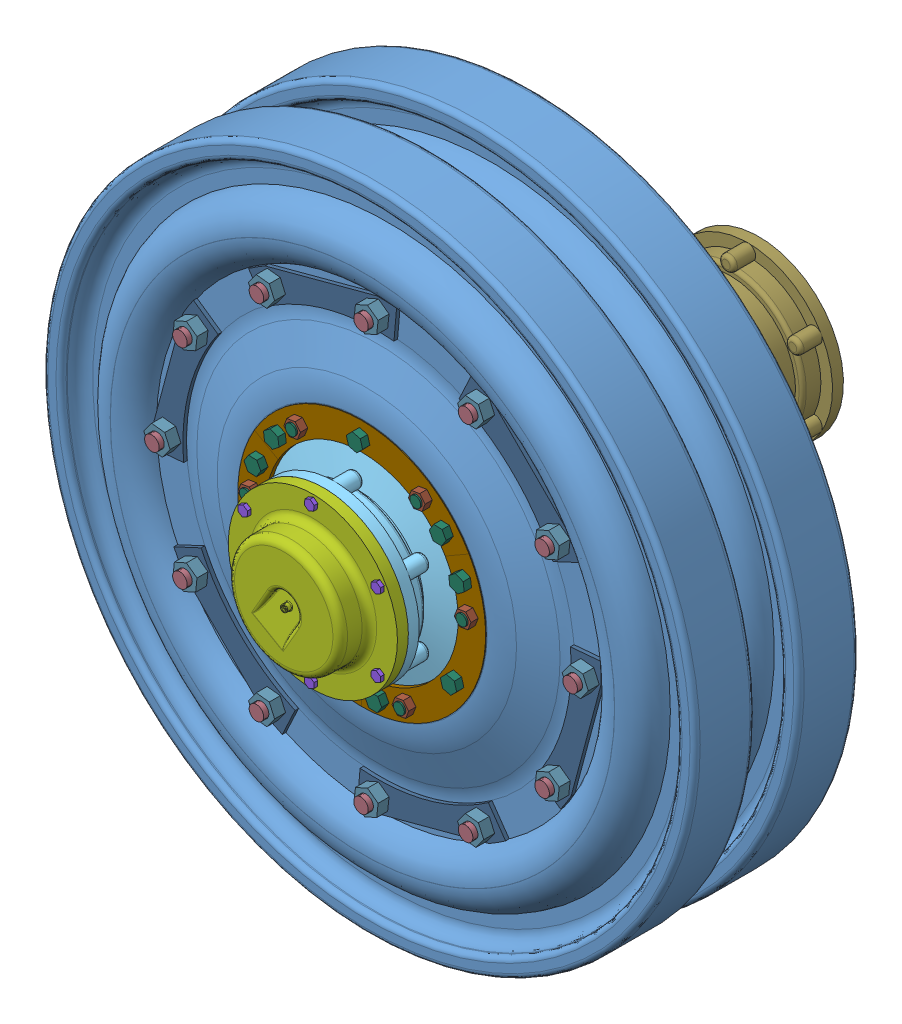
SolidWorks assembly Road Wheel - Outboard, configuration Default. Lengths in mm.
Overall size (31.05 31.05 16.2).
119 component instances, 15 part files, 92 mates.
Components (placement in the parent):
- Road Wheel-1: Road Wheel [Default] at (-21.9237 -2.6593 13.6423) size (22.73 22.73 3.09)
- Road Wheel-2: Road Wheel [Default] at (-21.9237 -2.6593 10.0228) x (0.5 -0.866025 0) z (0 0 -1) size (22.73 22.73 3.09)
- Road Wheel Space-1: Road Wheel Space [Default] at (-21.9237 -2.6593 10.6641) size (15.62 15.62 2.34)
- Road Wheel Bearing Assembly-1: Road Wheel Bearing Assembly [Default] at (-21.6388 -3.4173 13.177) x (0.656083 -0.754689 0) z (-0.754689 -0.656083 0) size (6.56 1.78 6.5)
  - Road Wheel Bearing-1: Road Wheel Bearing [Default] at (-0.759 1.0051 -0.2823) size (6.25 1.78 6.25)
  - Road Wheel Bearing Roller-1: Road Wheel Bearing Roller [Default] at (-0.759 -0.5628 2.4983) x (-0.999426 -0.00354 0.033681) z (0 0.994522 0.104528) size (0.64 0.64 1.4)
  - Road Wheel Bearing Roller-2: Road Wheel Bearing Roller [Default] at (-3.2936 0.8266 -1.7456) x (0.789274 0.103648 0.60523) z (0.090524 -0.994522 0.052264) size (0.64 0.64 1.4)
  - Road Wheel Bearing Roller-3: Road Wheel Bearing Roller [Default] at (-0.759 0.8266 -3.209) x (1 0 0) z (0 -0.994522 0.104528) size (0.64 0.64 1.4)
  - Road Wheel Bearing Roller-4: Road Wheel Bearing Roller [Default] at (0.242 0.8266 -3.0325) x (0.927484 0.003582 0.373846) z (-0.035751 -0.994522 0.098225) size (0.64 0.64 1.4)
  - Road Wheel Bearing Roller-5: Road Wheel Bearing Roller [Default] at (-2.5464 -0.5628 1.8478) x (0.99582 0.061868 0.06719) z (-0.06719 0.994522 0.080073) size (0.64 0.64 1.4)
  - Road Wheel Bearing Roller-6: Road Wheel Bearing Roller [Default] at (-3.4974 -0.5628 0.2005) x (0.979533 0.098182 0.175711) z (-0.10294 0.994522 0.018151) size (0.64 0.64 1.4)
  - Road Wheel Bearing Roller-7: Road Wheel Bearing Roller [Default] at (-2.6402 0.8266 -2.5243) x (0.99582 0.061868 -0.06719) z (0.06719 -0.994522 0.080073) size (0.64 0.64 1.4)
  - Road Wheel Bearing Roller-8: Road Wheel Bearing Roller [Default] at (-3.1671 -0.5628 1.108) x (0.992212 0.085557 0.090524) z (-0.090524 0.994522 0.052264) size (0.64 0.64 1.4)
  - Road Wheel Bearing Roller-9: Road Wheel Bearing Roller [Default] at (-1.71 -0.5628 2.3306) x (0.998836 0.032375 0.035751) z (-0.035751 0.994522 0.098225) size (0.64 0.64 1.4)
  - Road Wheel Bearing Roller-10: Road Wheel Bearing Roller [Default] at (-1.76 0.8266 -3.0325) x (0.998836 0.032375 -0.035751) z (0.035751 -0.994522 0.098225) size (0.64 0.64 1.4)
  - Road Wheel Bearing Roller-11: Road Wheel Bearing Roller [Default] at (-3.6412 0.8266 -0.7905) x (0.986505 0.104412 0.126122) z (0.10294 -0.994522 0.018151) size (0.64 0.64 1.4)
  - Road Wheel Bearing Roller-12: Road Wheel Bearing Roller [Default] at (2.1232 0.8266 -0.7905) x (0.885883 -0.083366 0.456356) z (-0.10294 -0.994522 0.018151) size (0.64 0.64 1.4)
  - Road Wheel Bearing Roller-13: Road Wheel Bearing Roller [Default] at (1.6491 -0.5628 1.108) x (0.992212 -0.085557 -0.090524) z (0.090524 0.994522 0.052264) size (0.64 0.64 1.4)
  - Road Wheel Bearing Roller-14: Road Wheel Bearing Roller [Default] at (1.0284 -0.5628 1.8478) x (0.874291 -0.097355 0.47554) z (0.06719 0.994522 0.080073) size (0.64 0.64 1.4)
  - Road Wheel Bearing Roller-15: Road Wheel Bearing Roller [Default] at (1.1222 0.8266 -2.5243) x (0.913673 -0.093574 -0.395532) z (-0.06719 -0.994522 0.080073) size (0.64 0.64 1.4)
  - Road Wheel Bearing Roller-16: Road Wheel Bearing Roller [Default] at (1.7756 0.8266 -1.7456) x (0.899555 -0.059136 0.432785) z (-0.090524 -0.994522 0.052264) size (0.64 0.64 1.4)
  - Road Wheel Bearing Roller-17: Road Wheel Bearing Roller [Default] at (1.9794 -0.5628 0.2005) x (0.989592 -0.100551 -0.10294) z (0.10294 0.994522 0.018151) size (0.64 0.64 1.4)
  - Road Wheel Bearing Roller-18: Road Wheel Bearing Roller [Default] at (0.192 -0.5628 2.3306) x (0.70634 -0.094677 0.701512) z (0.035751 0.994522 0.098225) size (0.64 0.64 1.4)
- Road Wheel Bearing Assembly-2: Road Wheel Bearing Assembly [Default] at (-21.3767 -3.2564 10.4881) x (0.37605 -0.926599 0) z (0.926599 0.37605 0) size (6.56 1.78 6.5)
  - Road Wheel Bearing-1: Road Wheel Bearing [Default] at (-0.759 1.0051 -0.2823) size (6.25 1.78 6.25)
  - Road Wheel Bearing Roller-1: Road Wheel Bearing Roller [Default] at (-0.759 -0.5628 2.4983) x (-0.999426 -0.00354 0.033681) z (0 0.994522 0.104528) size (0.64 0.64 1.4)
  - Road Wheel Bearing Roller-2: Road Wheel Bearing Roller [Default] at (-3.2936 0.8266 -1.7456) x (0.789274 0.103648 0.60523) z (0.090524 -0.994522 0.052264) size (0.64 0.64 1.4)
  - Road Wheel Bearing Roller-3: Road Wheel Bearing Roller [Default] at (-0.759 0.8266 -3.209) x (1 0 0) z (0 -0.994522 0.104528) size (0.64 0.64 1.4)
  - Road Wheel Bearing Roller-4: Road Wheel Bearing Roller [Default] at (0.242 0.8266 -3.0325) x (0.927484 0.003582 0.373846) z (-0.035751 -0.994522 0.098225) size (0.64 0.64 1.4)
  - Road Wheel Bearing Roller-5: Road Wheel Bearing Roller [Default] at (-2.5464 -0.5628 1.8478) x (0.99582 0.061868 0.06719) z (-0.06719 0.994522 0.080073) size (0.64 0.64 1.4)
  - Road Wheel Bearing Roller-6: Road Wheel Bearing Roller [Default] at (-3.4974 -0.5628 0.2005) x (0.979533 0.098182 0.175711) z (-0.10294 0.994522 0.018151) size (0.64 0.64 1.4)
  - Road Wheel Bearing Roller-7: Road Wheel Bearing Roller [Default] at (-2.6402 0.8266 -2.5243) x (0.99582 0.061868 -0.06719) z (0.06719 -0.994522 0.080073) size (0.64 0.64 1.4)
  - Road Wheel Bearing Roller-8: Road Wheel Bearing Roller [Default] at (-3.1671 -0.5628 1.108) x (0.992212 0.085557 0.090524) z (-0.090524 0.994522 0.052264) size (0.64 0.64 1.4)
  - Road Wheel Bearing Roller-9: Road Wheel Bearing Roller [Default] at (-1.71 -0.5628 2.3306) x (0.998836 0.032375 0.035751) z (-0.035751 0.994522 0.098225) size (0.64 0.64 1.4)
  - Road Wheel Bearing Roller-10: Road Wheel Bearing Roller [Default] at (-1.76 0.8266 -3.0325) x (0.998836 0.032375 -0.035751) z (0.035751 -0.994522 0.098225) size (0.64 0.64 1.4)
  - Road Wheel Bearing Roller-11: Road Wheel Bearing Roller [Default] at (-3.6412 0.8266 -0.7905) x (0.986505 0.104412 0.126122) z (0.10294 -0.994522 0.018151) size (0.64 0.64 1.4)
  - Road Wheel Bearing Roller-12: Road Wheel Bearing Roller [Default] at (2.1232 0.8266 -0.7905) x (0.885883 -0.083366 0.456356) z (-0.10294 -0.994522 0.018151) size (0.64 0.64 1.4)
  - Road Wheel Bearing Roller-13: Road Wheel Bearing Roller [Default] at (1.6491 -0.5628 1.108) x (0.992212 -0.085557 -0.090524) z (0.090524 0.994522 0.052264) size (0.64 0.64 1.4)
  - Road Wheel Bearing Roller-14: Road Wheel Bearing Roller [Default] at (1.0284 -0.5628 1.8478) x (0.874291 -0.097355 0.47554) z (0.06719 0.994522 0.080073) size (0.64 0.64 1.4)
  - Road Wheel Bearing Roller-15: Road Wheel Bearing Roller [Default] at (1.1222 0.8266 -2.5243) x (0.913673 -0.093574 -0.395532) z (-0.06719 -0.994522 0.080073) size (0.64 0.64 1.4)
  - Road Wheel Bearing Roller-16: Road Wheel Bearing Roller [Default] at (1.7756 0.8266 -1.7456) x (0.899555 -0.059136 0.432785) z (-0.090524 -0.994522 0.052264) size (0.64 0.64 1.4)
  - Road Wheel Bearing Roller-17: Road Wheel Bearing Roller [Default] at (1.9794 -0.5628 0.2005) x (0.989592 -0.100551 -0.10294) z (0.10294 0.994522 0.018151) size (0.64 0.64 1.4)
  - Road Wheel Bearing Roller-18: Road Wheel Bearing Roller [Default] at (0.192 -0.5628 2.3306) x (0.70634 -0.094677 0.701512) z (0.035751 0.994522 0.098225) size (0.64 0.64 1.4)
- Road Wheel Bearing Cover-1: Road Wheel Bearing Cover [Default] at (-21.9237 -2.6593 14.563) x (-0.04964 -0.998767 0) z (-0.998767 0.04964 0) size (8.64 2.08 8.64)
- Road Wheel Axle Main Nut-3: Road Wheel Axle Main Nut [Default] at (-21.4032 -5.4723 14.7408) size (3.1 3.08 1.27)
- Road Wheel Grease Cover-1: Road Wheel Grease Cover [Default] at (-21.9237 -2.6593 16.2648) x (0.5 0.866025 0) z (0.866025 -0.5 0) size (5.89 1.41 5.89)
- Road Wheel Grease Cover Bolt-1: Road Wheel Grease Cover Bolt [Default] at (-21.9237 -5.3382 16.6458) x (-0.999673 -0.025557 0) z (0 0 -1) size (0.34 0.38 1.4)
- Road Wheel Grease Cover Bolt-2: Road Wheel Grease Cover Bolt [Default] at (-21.9237 0.0196 16.6458) x (0.54039 0.841415 0) z (0 0 -1) size (0.34 0.38 1.4)
- Road Wheel Grease Cover Bolt-3: Road Wheel Grease Cover Bolt [Default] at (-19.6038 -3.9987 16.6458) x (-0.999673 -0.025557 0) z (0 0 -1) size (0.34 0.38 1.4)
- Road Wheel Grease Cover Bolt-4: Road Wheel Grease Cover Bolt [Default] at (-24.2437 -1.3199 16.6458) x (-0.999673 -0.025557 0) z (0 0 -1) size (0.34 0.38 1.4)
- Road Wheel Grease Cover Bolt-5: Road Wheel Grease Cover Bolt [Default] at (-24.2437 -3.9987 16.6458) x (-0.999673 -0.025557 0) z (0 0 -1) size (0.34 0.38 1.4)
- Road Wheel Grease Cover Bolt-6: Road Wheel Grease Cover Bolt [Default] at (-19.6038 -1.3199 16.6458) x (-0.999673 -0.025557 0) z (0 0 -1) size (0.34 0.38 1.4)
- Retainer Plate-1: Retainer Plate [Default] at (-21.9237 -2.6593 14.563) x (-0.5 0.866025 0) z (0 0 1) size (7.48 2.64 0.38)
- Retainer Plate-2: Retainer Plate [Default] at (-21.9237 -2.6593 14.563) x (-0.5 -0.866025 0) z (0 0 1) size (7.48 2.64 0.38)
- Retainer Plate-3: Retainer Plate [Default] at (-21.9237 -2.6593 14.563) size (7.48 2.64 0.38)
- Retainer Plate-4: Retainer Plate [Default] at (-21.9237 -2.6593 8.721) x (-0.5 -0.866025 0) z (0 0 1) size (7.48 2.64 0.38)
- Retainer Plate-5: Retainer Plate [Default] at (-21.9237 -2.6593 8.721) size (7.48 2.64 0.38)
- Retainer Plate-6: Retainer Plate [Default] at (-21.9237 -2.6593 8.721) x (-0.5 0.866025 0) z (0 0 1) size (7.48 2.64 0.38)
- Nut Retainer Plate-1: Nut Retainer Plate [Default] at (-21.9237 -2.6593 14.2836) x (0.5 0.866025 0) z (0 0 1) size (5.16 2.27 0.13)
- Nut Retainer Plate-2: Nut Retainer Plate [Default] at (-21.9237 -2.6593 14.2836) size (5.16 2.27 0.13)
- Nut Retainer Plate-3: Nut Retainer Plate [Default] at (-21.9237 -2.6593 14.2836) x (0.5 -0.866025 0) z (0 0 1) size (5.16 2.27 0.13)
- Nut Retainer Plate-4: Nut Retainer Plate [Default] at (-21.9237 -2.6593 14.2836) x (-0.5 0.866025 0) z (0 0 1) size (5.16 2.27 0.13)
- Nut Retainer Plate-5: Nut Retainer Plate [Default] at (-21.9237 -2.6593 14.2836) x (-1 0 0) z (0 0 1) size (5.16 2.27 0.13)
- Nut Retainer Plate-6: Nut Retainer Plate [Default] at (-21.9237 -2.6593 14.2836) x (-0.5 -0.866025 0) z (0 0 1) size (5.16 2.27 0.13)
- Road Wheel Bearing nut-2: Road Wheel Bearing nut [Default] at (-25.4383 -3.1945 8.467) size (0.58 0.55 0.25)
- Wheel Bearing Cover - Long-1: Wheel Bearing Cover - Long [Default] at (-21.9237 -2.6593 9.102) x (0.04964 -0.998767 0) z (0.998767 0.04964 0) size (8.64 8 8.64)
- Road Wheel Main Bolt-1: Road Wheel Main Bolt [Default] at (-28.2349 -6.303 9.3814) x (0.131887 0.991265 0) z (0 0 1) size (0.95 1.02 5.97)
- Road Wheel Main Nut-4: Road Wheel Main Nut [Default] at (-29.206 -3.6122 14.4106) x (-0.986683 -0.162654 0) z (0 0 1) size (0.89 0.88 0.38)
- Road Wheel Bearing Bolt-1: Road Wheel Bearing Bolt [Default] at (-25.2013 -4.5516 14.944) x (-0.923728 -0.383049 0) z (0 0 -1) size (0.54 0.58 6.78)
- Road Wheel Main Nut-5: Road Wheel Main Nut [Default] at (-28.7068 0.1566 14.4106) x (-0.93582 0.352479 0) z (0 0 1) size (0.89 0.88 0.38)
- Road Wheel Main Nut-6: Road Wheel Main Nut [Default] at (-26.3901 3.1709 14.4106) x (-0.634204 0.773166 0) z (0 0 1) size (0.89 0.88 0.38)
- Road Wheel Main Nut-7: Road Wheel Main Nut [Default] at (-22.8766 4.6229 14.4106) x (-0.162654 0.986683 0) z (0 0 1) size (0.89 0.88 0.38)
- Road Wheel Main Nut-8: Road Wheel Main Nut [Default] at (-19.1078 4.1237 14.4106) x (0.352479 0.93582 0) z (0 0 1) size (0.89 0.88 0.38)
- Road Wheel Main Nut-9: Road Wheel Main Nut [Default] at (-16.0936 1.807 14.4106) x (0.773166 0.634204 0) z (0 0 1) size (0.89 0.88 0.38)
- Road Wheel Main Nut-10: Road Wheel Main Nut [Default] at (-14.6415 -1.7064 14.4106) x (0.986683 0.162654 0) z (0 0 1) size (0.89 0.88 0.38)
- Road Wheel Main Nut-11: Road Wheel Main Nut [Default] at (-15.1407 -5.4752 14.4106) x (0.93582 -0.352479 0) z (0 0 1) size (0.89 0.88 0.38)
- Road Wheel Main Nut-12: Road Wheel Main Nut [Default] at (-17.4574 -8.4895 14.4106) x (0.634204 -0.773166 0) z (0 0 1) size (0.89 0.88 0.38)
- Road Wheel Main Nut-13: Road Wheel Main Nut [Default] at (-20.9709 -9.9416 14.4106) x (0.162654 -0.986683 0) z (0 0 1) size (0.89 0.88 0.38)
- Road Wheel Main Nut-14: Road Wheel Main Nut [Default] at (-24.7397 -9.4424 14.4106) x (-0.352479 -0.93582 0) z (0 0 1) size (0.89 0.88 0.38)
- Road Wheel Main Nut-15: Road Wheel Main Nut [Default] at (-27.7539 -7.1256 14.4106) x (-0.773166 -0.634204 0) z (0 0 1) size (0.89 0.88 0.38)
- Road Wheel Main Bolt-2: Road Wheel Main Bolt [Default] at (-29.2112 -2.6593 9.3814) x (0.60985 0.792517 0) z (0 0 1) size (0.95 1.02 5.97)
- Road Wheel Main Bolt-3: Road Wheel Main Bolt [Default] at (-28.2349 0.9844 9.3814) x (0.924404 0.381415 0) z (0 0 1) size (0.95 1.02 5.97)
- Road Wheel Main Bolt-4: Road Wheel Main Bolt [Default] at (-25.5675 3.6518 9.3814) x (0.991265 -0.131887 0) z (0 0 1) size (0.95 1.02 5.97)
- Road Wheel Main Bolt-5: Road Wheel Main Bolt [Default] at (-21.9237 4.6282 9.3814) x (0.792517 -0.60985 0) z (0 0 1) size (0.95 1.02 5.97)
- Road Wheel Main Bolt-6: Road Wheel Main Bolt [Default] at (-18.28 3.6518 9.3814) x (0.381415 -0.924404 0) z (0 0 1) size (0.95 1.02 5.97)
- Road Wheel Main Bolt-7: Road Wheel Main Bolt [Default] at (-15.6126 0.9844 9.3814) x (-0.131887 -0.991265 0) z (0 0 1) size (0.95 1.02 5.97)
- Road Wheel Main Bolt-8: Road Wheel Main Bolt [Default] at (-14.6363 -2.6593 9.3814) x (-0.60985 -0.792517 0) z (0 0 1) size (0.95 1.02 5.97)
- Road Wheel Main Bolt-9: Road Wheel Main Bolt [Default] at (-15.6126 -6.303 9.3814) x (-0.924404 -0.381415 0) z (0 0 1) size (0.95 1.02 5.97)
- Road Wheel Main Bolt-10: Road Wheel Main Bolt [Default] at (-18.28 -8.9704 9.3814) x (-0.991265 0.131887 0) z (0 0 1) size (0.95 1.02 5.97)
- Road Wheel Main Bolt-11: Road Wheel Main Bolt [Default] at (-21.9237 -9.9468 9.3814) x (-0.792517 0.60985 0) z (0 0 1) size (0.95 1.02 5.97)
- Road Wheel Main Bolt-12: Road Wheel Main Bolt [Default] at (-25.5675 -8.9704 9.3814) x (-0.381415 0.924404 0) z (0 0 1) size (0.95 1.02 5.97)
- Road Wheel Bearing Bolt-2: Road Wheel Bearing Bolt [Default] at (-22.5809 -6.3864 14.944) x (0.698183 -0.71592 0) z (0 0 -1) size (0.54 0.58 6.78)
- Road Wheel Bearing Bolt-3: Road Wheel Bearing Bolt [Default] at (-23.5232 -6.0893 8.721) size (0.54 0.58 6.78)
- Road Wheel Bearing Bolt-4: Road Wheel Bearing Bolt [Default] at (-25.6939 -2.3295 8.721) size (0.54 0.58 6.78)
- Road Wheel Bearing Bolt-5: Road Wheel Bearing Bolt [Default] at (-25.4801 -1.3649 14.944) x (0.078468 -0.996917 0) z (0 0 -1) size (0.54 0.58 6.78)
- Road Wheel Bearing nut-3: Road Wheel Bearing nut [Default] at (-25.9309 -0.9724 14.944) size (0.58 0.55 0.25)
- Road Wheel Bearing nut-4: Road Wheel Bearing nut [Default] at (-23.7602 -4.7322 14.944) size (0.58 0.55 0.25)
- Road Wheel Bearing nut-5: Road Wheel Bearing nut [Default] at (-22.8179 -5.0293 8.467) size (0.58 0.55 0.25)
- Road Wheel Bearing nut-6: Road Wheel Bearing nut [Default] at (-25.7171 -0.0078 8.467) size (0.58 0.55 0.25)
- Road Wheel Bearing nut-7: Road Wheel Bearing nut [Default] at (-19.4242 -2.2487 8.467) x (-0.5 0.866025 0) z (0 0 1) size (0.58 0.55 0.25)
- Road Wheel Bearing nut-8: Road Wheel Bearing nut [Default] at (-23.5291 -0.6999 8.467) x (-0.5 -0.866025 0) z (0 0 1) size (0.58 0.55 0.25)
- Road Wheel Bearing nut-9: Road Wheel Bearing nut [Default] at (-19.703 -5.4354 8.467) x (-0.5 0.866025 0) z (0 0 1) size (0.58 0.55 0.25)
- Road Wheel Bearing nut-10: Road Wheel Bearing nut [Default] at (-20.6299 0.652 8.467) x (-0.5 -0.866025 0) z (0 0 1) size (0.58 0.55 0.25)
- Road Wheel Bearing nut-11: Road Wheel Bearing nut [Default] at (-22.3233 -7.2702 8.467) x (-0.5 0.866025 0) z (0 0 1) size (0.58 0.55 0.25)
- Road Wheel Bearing nut-12: Road Wheel Bearing nut [Default] at (-17.7308 -0.6999 8.467) x (-0.5 -0.866025 0) z (0 0 1) size (0.58 0.55 0.25)
- Road Wheel Bearing Bolt-6: Road Wheel Bearing Bolt [Default] at (-21.2666 -6.3864 14.944) x (0.824121 0.566414 0) z (0 0 -1) size (0.54 0.58 6.78)
- Road Wheel Bearing Bolt-7: Road Wheel Bearing Bolt [Default] at (-19.0246 -0.2266 14.944) x (-0.902589 0.430503 0) z (0 0 -1) size (0.54 0.58 6.78)
- Road Wheel Bearing Bolt-8: Road Wheel Bearing Bolt [Default] at (-20.3243 -6.0893 8.721) x (-0.5 0.866025 0) z (0 0 1) size (0.54 0.58 6.78)
- Road Wheel Bearing Bolt-9: Road Wheel Bearing Bolt [Default] at (-19.753 0.4409 8.721) x (-0.5 -0.866025 0) z (0 0 1) size (0.54 0.58 6.78)
- Road Wheel Bearing nut-13: Road Wheel Bearing nut [Default] at (-21.3811 -6.9731 14.944) x (-0.5 0.866025 0) z (0 0 1) size (0.58 0.55 0.25)
- Road Wheel Bearing nut-14: Road Wheel Bearing nut [Default] at (-18.4592 -0.0325 14.944) x (-0.5 -0.866025 0) z (0 0 1) size (0.58 0.55 0.25)
- Road Wheel Bearing Bolt-10: Road Wheel Bearing Bolt [Default] at (-18.6462 -4.5516 14.944) x (0.793594 -0.608447 0) z (0 0 -1) size (0.54 0.58 6.78)
- Road Wheel Bearing Bolt-11: Road Wheel Bearing Bolt [Default] at (-21.9237 1.1253 14.944) x (0.130134 0.991496 0) z (0 0 -1) size (0.54 0.58 6.78)
- Road Wheel Bearing nut-15: Road Wheel Bearing nut [Default] at (-19.2103 -3.2133 14.944) x (-0.5 0.866025 0) z (0 0 1) size (0.58 0.55 0.25)
- Road Wheel Bearing nut-16: Road Wheel Bearing nut [Default] at (-22.8007 -0.0325 14.944) x (-0.5 -0.866025 0) z (0 0 1) size (0.58 0.55 0.25)
- Road Wheel Bearing Bolt-12: Road Wheel Bearing Bolt [Default] at (-18.1535 -2.3295 8.721) x (-0.5 0.866025 0) z (0 0 1) size (0.54 0.58 6.78)
- Road Wheel Bearing Bolt-13: Road Wheel Bearing Bolt [Default] at (-24.0945 0.4409 8.721) x (-0.5 -0.866025 0) z (0 0 1) size (0.54 0.58 6.78)
- Road Wheel Bearing Bolt-14: Road Wheel Bearing Bolt [Default] at (-18.3674 -1.3649 14.944) x (0.270913 0.962604 0) z (0 0 -1) size (0.54 0.58 6.78)
- Road Wheel Bearing Bolt-15: Road Wheel Bearing Bolt [Default] at (-24.8229 -0.2266 14.944) x (-0.969096 -0.246684 0) z (0 0 -1) size (0.54 0.58 6.78)
Mates (geometry in assembly coordinates):
- Concentric1: concentric aligned: cylinder of Road Wheel-1 through (-21.9237 -2.6593 14.69) axis (0 0 -1) radius 11.3665; cylinder of Road Wheel Space-1 through (-21.9237 -2.6593 13.0009) axis (0 0 -1) radius 6.7644
- Coincident1: coincident anti-aligned: plane of Road Wheel-1 through (-21.9237 -2.6593 13.0009) normal (0 0 -1); plane of Road Wheel Space-1 through (-21.9237 -2.6593 13.0009) normal (0 0 1)
- Concentric2: concentric aligned: cylinder of Road Wheel-1 through (-25.5675 3.6518 15.002) axis (0 0 -1) radius 0.254; cylinder of Road Wheel Space-1 through (-25.5675 3.6518 13.0009) axis (0 0 -1) radius 0.3175
- Coincident2: coincident anti-aligned: plane of Road Wheel-2 through (-21.9237 -2.6593 10.6641) normal (0 0 1); plane of Road Wheel Space-1 through (-21.9237 -2.6593 10.6641) normal (0 0 -1)
- Concentric3: concentric anti-aligned: cylinder of Road Wheel-1 through (-21.9237 -2.6593 14.69) axis (0 0 -1) radius 11.3665; cylinder of Road Wheel-2 through (-21.9237 -2.6593 8.975) axis (0 0 1) radius 11.3665
- Coincident3: coincident aligned: plane of Road Wheel-1 through (-21.9237 -2.6593 14.182) normal (0 0 1); plane of Road Wheel Bearing Assembly-1/Road Wheel Bearing-1 through (-21.9237 -2.6593 14.182) normal (0 0 1)
- Concentric5: concentric anti-aligned: cylinder of Road Wheel-1 through (-21.9237 -2.6593 14.9186) axis (0 0 -1) radius 4.318; cylinder of Road Wheel Bearing Assembly-1/Road Wheel Bearing-1 through (-21.9237 -2.6593 12.404) axis (0 0 1) radius 1.1303
- Coincident4: coincident aligned: plane of Road Wheel-2 through (-21.9237 -2.6593 9.483) normal (0 0 -1); plane of Road Wheel Bearing Assembly-2/Road Wheel Bearing-1 through (-21.9237 -2.6593 9.483) normal (0 0 -1)
- Concentric6: concentric anti-aligned: cylinder of Road Wheel-2 through (-21.9237 -2.6593 8.7464) axis (0 0 1) radius 4.318; cylinder of Road Wheel Bearing Assembly-2/Road Wheel Bearing-1 through (-21.9237 -2.6593 11.261) axis (0 0 -1) radius 1.1303
- Coincident5: coincident anti-aligned: plane of Road Wheel-1 through (-21.9237 -2.6593 14.182) normal (0 0 1); plane of Road Wheel Bearing Cover-1 through (-21.9237 -2.6593 14.182) normal (0 0 -1)
- Concentric7: concentric anti-aligned: cylinder of Road Wheel-1 through (-21.9237 -2.6593 14.9186) axis (0 0 -1) radius 4.318; cylinder of Road Wheel Bearing Cover-1 through (-21.9237 -2.6593 14.182) axis (0 0 1) radius 4.318
- Concentric8: concentric anti-aligned: cylinder of Road Wheel-1 through (-21.9237 1.1253 11.2937) axis (0 0 1) radius 0.1905; cylinder of Road Wheel Bearing Cover-1 through (-21.9237 1.1253 15.1018) axis (0 0 -1) radius 0.1905
- Coincident6: coincident anti-aligned: plane of Road Wheel Bearing Cover-1 through (-21.9237 -2.6593 14.7408) normal (0 0 1); plane of Road Wheel Axle Main Nut-3 through (-19.9489 -0.7189 14.7408) normal (0 0 -1)
- Concentric9: concentric anti-aligned: cylinder of Road Wheel Bearing Cover-1 through (-21.9237 -2.6593 10.8414) axis (0 0 1) radius 1.1811; cylinder of Road Wheel Axle Main Nut-3 through (-21.9237 -2.6593 16.0108) axis (0 0 -1) radius 1.1303
- Coincident7: coincident anti-aligned: plane of Road Wheel Grease Cover-1 through (-21.9237 -2.6593 16.2648) normal (0 0 -1); plane of Road Wheel Bearing Cover-1 through (-21.9237 -2.6593 16.2648) normal (0 0 1)
- Concentric10: concentric aligned: cylinder of Road Wheel Bearing Cover-1 through (-21.9237 -2.6593 16.2648) axis (0 0 -1) radius 2.9464; cylinder of Road Wheel Grease Cover-1 through (-21.9237 -2.6593 16.6458) axis (0 0 -1) radius 2.9464
- Concentric11: concentric aligned: cylinder of Road Wheel Bearing Cover-1 through (-19.6038 -1.3199 15.3758) axis (0 0 1) radius 0.127; cylinder of Road Wheel Grease Cover-1 through (-19.6038 -1.3199 15.9056) axis (0 0 1) radius 0.127
- Coincident8: coincident aligned: plane of Road Wheel Grease Cover Bolt-1 through (-22.0916 -5.4233 16.7728) normal (0 0 1); plane of Road Wheel Grease Cover Bolt-3 through (-19.7717 -4.0839 16.7728) normal (0 0 1)
- Coincident9: coincident aligned: plane of Road Wheel Grease Cover Bolt-1 through (-22.0916 -5.4233 16.7728) normal (0 0 1); plane of Road Wheel Grease Cover Bolt-2 through (-21.8999 0.2063 16.7728) normal (0 0 1)
- Coincident10: coincident aligned: plane of Road Wheel Grease Cover Bolt-2 through (-21.8999 0.2063 16.7728) normal (0 0 1); plane of Road Wheel Grease Cover Bolt-4 through (-24.4116 -1.405 16.7728) normal (0 0 1)
- Coincident11: coincident aligned: plane of Road Wheel Grease Cover Bolt-4 through (-24.4116 -1.405 16.7728) normal (0 0 1); plane of Road Wheel Grease Cover Bolt-5 through (-24.4116 -4.0839 16.7728) normal (0 0 1)
- Coincident12: coincident aligned: plane of Road Wheel Grease Cover Bolt-5 through (-24.4116 -4.0839 16.7728) normal (0 0 1); plane of Road Wheel Grease Cover Bolt-6 through (-19.7717 -1.405 16.7728) normal (0 0 1)
- Concentric12: concentric aligned: cylinder of Road Wheel Grease Cover-1 through (-19.6038 -3.9987 15.9056) axis (0 0 1) radius 0.127; cylinder of Road Wheel Grease Cover Bolt-3 through (-19.6038 -3.9987 15.3758) axis (0 0 1) radius 0.127
- Concentric13: concentric aligned: cylinder of Road Wheel Bearing Cover-1 through (-21.9237 -5.3382 15.3758) axis (0 0 1) radius 0.127; cylinder of Road Wheel Grease Cover Bolt-1 through (-21.9237 -5.3382 15.3758) axis (0 0 1) radius 0.127
- Concentric14: concentric aligned: cylinder of Road Wheel Bearing Cover-1 through (-24.2437 -3.9987 15.3758) axis (0 0 1) radius 0.127; cylinder of Road Wheel Grease Cover Bolt-5 through (-24.2437 -3.9987 15.3758) axis (0 0 1) radius 0.127
- Concentric15: concentric aligned: cylinder of Road Wheel Bearing Cover-1 through (-24.2437 -1.3199 15.3758) axis (0 0 1) radius 0.127; cylinder of Road Wheel Grease Cover Bolt-4 through (-24.2437 -1.3199 15.3758) axis (0 0 1) radius 0.127
- Concentric16: concentric aligned: cylinder of Road Wheel Bearing Cover-1 through (-21.9237 0.0196 15.3758) axis (0 0 1) radius 0.127; cylinder of Road Wheel Grease Cover Bolt-2 through (-21.9237 0.0196 15.3758) axis (0 0 1) radius 0.127
- Concentric17: concentric aligned: cylinder of Road Wheel Grease Cover-1 through (-19.6038 -1.3199 15.9056) axis (0 0 1) radius 0.127; cylinder of Road Wheel Grease Cover Bolt-6 through (-19.6038 -1.3199 15.3758) axis (0 0 1) radius 0.127
- Coincident13: coincident anti-aligned: plane of Road Wheel Grease Cover-1 through (-21.9237 -2.6593 16.6458) normal (0 0 1); plane of Road Wheel Grease Cover Bolt-3 through (-19.7717 -4.0839 16.6458) normal (0 0 -1)
- Coincident14: coincident aligned: plane of Retainer Plate-1 through (-21.9237 -2.6593 14.944) normal (0 0 1); plane of Retainer Plate-2 through (-21.9237 -2.6593 14.944) normal (0 0 1)
- Coincident15: coincident aligned: plane of Retainer Plate-2 through (-21.9237 -2.6593 14.944) normal (0 0 1); plane of Retainer Plate-3 through (-21.9237 -2.6593 14.944) normal (0 0 1)
- Coincident16: coincident anti-aligned: plane of Retainer Plate-2 through (-21.9237 -6.0215 14.944) normal (-1 0 0); plane of Retainer Plate-1 through (-21.9237 -6.0215 14.944) normal (1 0 0)
- Concentric18: concentric aligned: cylinder of Retainer Plate-1 through (-21.9237 -2.6593 14.944) axis (0 0 -1) radius 4.318; cylinder of Retainer Plate-2 through (-21.9237 -2.6593 14.944) axis (0 0 -1) radius 4.318
- Coincident17: coincident anti-aligned: plane of Retainer Plate-3 through (-24.8355 -0.9782 14.944) normal (-0.5 -0.866025 0); plane of Retainer Plate-1 through (-24.8355 -0.9782 14.944) normal (0.5 0.866025 0)
- Concentric19: concentric aligned: cylinder of Retainer Plate-1 through (-21.9237 -2.6593 14.944) axis (0 0 -1) radius 4.318; cylinder of Retainer Plate-3 through (-21.9237 -2.6593 14.944) axis (0 0 -1) radius 4.318
- Coincident18: coincident anti-aligned: plane of Road Wheel Bearing Cover-1 through (-21.9237 -2.6593 14.563) normal (0 0 1); plane of Retainer Plate-3 through (-21.9237 -2.6593 14.563) normal (0 0 -1)
- Concentric20: concentric aligned: cylinder of Road Wheel Bearing Cover-1 through (-25.4801 -1.3649 15.1018) axis (0 0 -1) radius 0.1905; cylinder of Retainer Plate-1 through (-25.4801 -1.3649 14.944) axis (0 0 -1) radius 0.1905
- Coincident19: coincident aligned: plane of Nut Retainer Plate-1 through (-21.9237 -2.6593 14.4106) normal (0 0 1); plane of Nut Retainer Plate-2 through (-21.9237 -2.6593 14.4106) normal (0 0 1)
- Coincident20: coincident aligned: plane of Nut Retainer Plate-2 through (-21.9237 -2.6593 14.4106) normal (0 0 1); plane of Nut Retainer Plate-3 through (-21.9237 -2.6593 14.4106) normal (0 0 1)
- Coincident21: coincident aligned: plane of Nut Retainer Plate-3 through (-21.9237 -2.6593 14.4106) normal (0 0 1); plane of Nut Retainer Plate-4 through (-21.9237 -2.6593 14.4106) normal (0 0 1)
- Coincident22: coincident aligned: plane of Nut Retainer Plate-4 through (-21.9237 -2.6593 14.4106) normal (0 0 1); plane of Nut Retainer Plate-5 through (-21.9237 -2.6593 14.4106) normal (0 0 1)
- Coincident23: coincident aligned: plane of Nut Retainer Plate-5 through (-21.9237 -2.6593 14.4106) normal (0 0 1); plane of Nut Retainer Plate-6 through (-21.9237 -2.6593 14.4106) normal (0 0 1)
- Concentric21: concentric aligned: cylinder of Road Wheel-1 through (-29.2112 -2.6593 15.002) axis (0 0 -1) radius 0.254; cylinder of Nut Retainer Plate-1 through (-29.2112 -2.6593 14.4106) axis (0 0 -1) radius 0.254
- Coincident24: coincident anti-aligned: plane of Road Wheel-1 through (-21.9237 -2.6593 14.2836) normal (0 0 1); plane of Nut Retainer Plate-1 through (-21.9237 -2.6593 14.2836) normal (0 0 -1)
- Concentric22: concentric aligned: cylinder of Road Wheel-1 through (-28.2349 0.9844 15.002) axis (0 0 -1) radius 0.254; cylinder of Nut Retainer Plate-1 through (-28.2349 0.9844 14.4106) axis (0 0 -1) radius 0.254
- Concentric23: concentric aligned: cylinder of Road Wheel-1 through (-25.5675 3.6518 15.002) axis (0 0 -1) radius 0.254; cylinder of Nut Retainer Plate-2 through (-25.5675 3.6518 14.4106) axis (0 0 -1) radius 0.254
- Concentric24: concentric aligned: cylinder of Road Wheel-1 through (-21.9237 4.6282 15.002) axis (0 0 -1) radius 0.254; cylinder of Nut Retainer Plate-2 through (-21.9237 4.6282 14.4106) axis (0 0 -1) radius 0.254
- Concentric25: concentric aligned: cylinder of Road Wheel-1 through (-18.28 3.6518 15.002) axis (0 0 -1) radius 0.254; cylinder of Nut Retainer Plate-3 through (-18.28 3.6518 14.4106) axis (0 0 -1) radius 0.254
- Concentric26: concentric aligned: cylinder of Road Wheel-1 through (-15.6126 0.9844 15.002) axis (0 0 -1) radius 0.254; cylinder of Nut Retainer Plate-3 through (-15.6126 0.9844 14.4106) axis (0 0 -1) radius 0.254
- Concentric27: concentric aligned: cylinder of Road Wheel-1 through (-28.2349 -6.303 15.002) axis (0 0 -1) radius 0.254; cylinder of Nut Retainer Plate-4 through (-28.2349 -6.303 14.4106) axis (0 0 -1) radius 0.254
- Concentric28: concentric aligned: cylinder of Road Wheel-1 through (-25.5675 -8.9704 15.002) axis (0 0 -1) radius 0.254; cylinder of Nut Retainer Plate-4 through (-25.5675 -8.9704 14.4106) axis (0 0 -1) radius 0.254
- Concentric30: concentric aligned: cylinder of Road Wheel-1 through (-21.9237 -9.9468 15.002) axis (0 0 -1) radius 0.254; cylinder of Nut Retainer Plate-5 through (-21.9237 -9.9468 14.4106) axis (0 0 -1) radius 0.254
- Concentric31: concentric aligned: cylinder of Road Wheel-1 through (-18.28 -8.9704 15.002) axis (0 0 -1) radius 0.254; cylinder of Nut Retainer Plate-5 through (-18.28 -8.9704 14.4106) axis (0 0 -1) radius 0.254
- Concentric32: concentric aligned: cylinder of Road Wheel-1 through (-15.6126 -6.303 15.002) axis (0 0 -1) radius 0.254; cylinder of Nut Retainer Plate-6 through (-15.6126 -6.303 14.4106) axis (0 0 -1) radius 0.254
- Concentric33: concentric aligned: cylinder of Road Wheel-1 through (-14.6363 -2.6593 15.002) axis (0 0 -1) radius 0.254; cylinder of Nut Retainer Plate-6 through (-14.6363 -2.6593 14.4106) axis (0 0 -1) radius 0.254
- Concentric34: concentric anti-aligned: cylinder of Road Wheel-1 through (-25.2013 -4.5516 11.2937) axis (0 0 1) radius 0.1905; cylinder of Road Wheel-2 through (-25.2013 -4.5516 12.3713) axis (0 0 -1) radius 0.1905
- Concentric35: concentric aligned: cylinder of Road Wheel Bearing Cover-1 through (-18.6462 -4.5516 15.1018) axis (0 0 -1) radius 0.1905; cylinder of Retainer Plate-2 through (-18.6462 -4.5516 14.944) axis (0 0 -1) radius 0.1905
- Coincident25: coincident anti-aligned: plane of Road Wheel-2 through (-21.9237 -2.6593 9.483) normal (0 0 -1); plane of Wheel Bearing Cover - Long-1 through (-21.9237 -2.6593 9.483) normal (0 0 1)
- Concentric36: concentric anti-aligned: cylinder of Road Wheel-2 through (-21.9237 -2.6593 8.7464) axis (0 0 1) radius 4.318; cylinder of Wheel Bearing Cover - Long-1 through (-21.9237 -2.6593 9.483) axis (0 0 -1) radius 4.318
- Concentric37: concentric anti-aligned: cylinder of Road Wheel-2 through (-21.9237 1.1253 12.3713) axis (0 0 -1) radius 0.1905; cylinder of Wheel Bearing Cover - Long-1 through (-21.9237 1.1253 8.5632) axis (0 0 1) radius 0.1905
- Coincident26: coincident anti-aligned: plane of Retainer Plate-6 through (-24.8355 -0.9782 9.102) normal (0.5 0.866025 0); plane of Retainer Plate-5 through (-24.8355 -0.9782 9.102) normal (-0.5 -0.866025 0)
- Concentric38: concentric aligned: cylinder of Retainer Plate-5 through (-21.9237 -2.6593 9.102) axis (0 0 -1) radius 3.3622; cylinder of Retainer Plate-6 through (-21.9237 -2.6593 9.102) axis (0 0 -1) radius 3.3622
- Coincident27: coincident aligned: plane of Retainer Plate-5 through (-21.9237 -2.6593 9.102) normal (0 0 1); plane of Retainer Plate-6 through (-21.9237 -2.6593 9.102) normal (0 0 1)
- Coincident28: coincident aligned: plane of Retainer Plate-4 through (-21.9237 -2.6593 9.102) normal (0 0 1); plane of Retainer Plate-5 through (-21.9237 -2.6593 9.102) normal (0 0 1)
- Coincident29: coincident anti-aligned: plane of Retainer Plate-4 through (-21.9237 -6.0215 9.102) normal (-1 0 0); plane of Retainer Plate-6 through (-21.9237 -6.0215 9.102) normal (1 0 0)
- Concentric39: concentric aligned: cylinder of Retainer Plate-4 through (-21.9237 -2.6593 9.102) axis (0 0 -1) radius 4.318; cylinder of Retainer Plate-6 through (-21.9237 -2.6593 9.102) axis (0 0 -1) radius 4.318
- Coincident30: coincident anti-aligned: plane of Retainer Plate-4 through (-21.9237 -2.6593 9.102) normal (0 0 1); plane of Wheel Bearing Cover - Long-1 through (-21.9237 -2.6593 9.102) normal (0 0 -1)
- Concentric40: concentric anti-aligned: cylinder of Wheel Bearing Cover - Long-1 through (-21.9237 1.1253 8.5632) axis (0 0 1) radius 0.1905; cylinder of Retainer Plate-5 through (-21.9237 1.1253 9.102) axis (0 0 -1) radius 0.1905
- Concentric42: concentric anti-aligned: cylinder of Road Wheel-2 through (-28.2349 -6.303 8.663) axis (0 0 1) radius 0.254; cylinder of Road Wheel Main Bolt-1 through (-28.2349 -6.303 14.9694) axis (0 0 -1) radius 0.254
- Coincident32: coincident anti-aligned: plane of Road Wheel-2 through (-21.9237 -2.6593 9.3814) normal (0 0 -1); plane of Road Wheel Main Bolt-1 through (-29.0056 -6.754 9.3814) normal (0 0 1)
- Concentric43: concentric anti-aligned: cylinder of Retainer Plate-1 through (-25.2013 -4.5516 14.944) axis (0 0 -1) radius 0.1905; cylinder of Road Wheel Bearing Bolt-1 through (-25.2013 -4.5516 8.4162) axis (0 0 1) radius 0.1905
- Coincident33: coincident anti-aligned: plane of Retainer Plate-1 through (-21.9237 -2.6593 14.944) normal (0 0 1); plane of Road Wheel Bearing Bolt-1 through (-25.121 -4.8337 14.944) normal (0 0 -1)
- Coincident34: coincident anti-aligned: plane of Retainer Plate-6 through (-21.9237 -2.6593 8.721) normal (0 0 -1); plane of Road Wheel Bearing nut-2 through (-25.0156 -4.7787 8.721) normal (0 0 1)
- Concentric44: concentric anti-aligned: cylinder of Road Wheel Bearing nut-2 through (-25.2013 -4.5516 8.721) axis (0 0 -1) radius 0.1905; cylinder of Road Wheel Bearing Bolt-1 through (-25.2013 -4.5516 8.4162) axis (0 0 1) radius 0.1905
- Coincident35: coincident anti-aligned: plane of Nut Retainer Plate-4 through (-21.9237 -2.6593 14.4106) normal (0 0 1); plane of Road Wheel Main Nut-4 through (-28.7033 -6.9444 14.4106) normal (0 0 -1)
- Concentric46: concentric aligned: cylinder of Road Wheel Main Bolt-1 through (-28.2349 -6.303 14.9694) axis (0 0 -1) radius 0.254; cylinder of Road Wheel Main Nut-4 through (-28.2349 -6.303 14.7916) axis (0 0 -1) radius 0.254
- Coincident36: coincident aligned: plane of Road Wheel Bearing Bolt-3 through (-23.5232 -6.0893 15.2488) normal (0 0 1); plane of Road Wheel Bearing Bolt-4 through (-25.6939 -2.3295 15.2488) normal (0 0 1)
- Concentric47: concentric aligned: cylinder of Retainer Plate-1 through (-23.5232 -6.0893 14.944) axis (0 0 -1) radius 0.1905; cylinder of Road Wheel Bearing Bolt-3 through (-23.5232 -6.0893 15.2488) axis (0 0 -1) radius 0.1905
- Concentric48: concentric aligned: cylinder of Retainer Plate-1 through (-25.6939 -2.3295 14.944) axis (0 0 -1) radius 0.1905; cylinder of Road Wheel Bearing Bolt-4 through (-25.6939 -2.3295 15.2488) axis (0 0 -1) radius 0.1905
- Coincident37: coincident anti-aligned: plane of Retainer Plate-6 through (-21.9237 -2.6593 8.721) normal (0 0 -1); plane of Road Wheel Bearing Bolt-3 through (-23.4893 -6.3807 8.721) normal (0 0 1)
- Concentric49: concentric aligned: cylinder of Road Wheel Bearing Bolt-3 through (-23.5232 -6.0893 15.2488) axis (0 0 -1) radius 0.1905; cylinder of Road Wheel Bearing nut-4 through (-23.5232 -6.0893 15.198) axis (0 0 -1) radius 0.1905
- Concentric50: concentric aligned: cylinder of Road Wheel Bearing Bolt-4 through (-25.6939 -2.3295 15.2488) axis (0 0 -1) radius 0.1905; cylinder of Road Wheel Bearing nut-3 through (-25.6939 -2.3295 15.198) axis (0 0 -1) radius 0.1905
- Coincident38: coincident aligned: plane of Road Wheel Bearing nut-3 through (-25.5083 -2.5565 15.198) normal (0 0 1); plane of Road Wheel Bearing nut-4 through (-23.3375 -6.3164 15.198) normal (0 0 1)
- Coincident39: coincident anti-aligned: plane of Retainer Plate-1 through (-21.9237 -2.6593 14.944) normal (0 0 1); plane of Road Wheel Bearing nut-3 through (-25.5083 -2.5565 14.944) normal (0 0 -1)
- Coincident40: coincident aligned: plane of Road Wheel Bearing Bolt-2 through (-22.5809 -6.3864 8.4162) normal (0 0 -1); plane of Road Wheel Bearing Bolt-5 through (-25.4801 -1.3649 8.4162) normal (0 0 -1)
- Concentric51: concentric anti-aligned: cylinder of Retainer Plate-1 through (-25.4801 -1.3649 14.944) axis (0 0 -1) radius 0.1905; cylinder of Road Wheel Bearing Bolt-5 through (-25.4801 -1.3649 8.4162) axis (0 0 1) radius 0.1905
- Coincident41: coincident aligned: circle of Retainer Plate-1; cylinder of Road Wheel Bearing Bolt-2 through (-22.5809 -6.3864 8.4162) axis (0 0 1) radius 0.1905
- Coincident42: coincident anti-aligned: plane of Retainer Plate-1 through (-21.9237 -2.6593 14.944) normal (0 0 1); plane of Road Wheel Bearing Bolt-5 through (-25.187 -1.3758 14.944) normal (0 0 -1)
- Coincident43: coincident aligned: plane of Road Wheel Bearing nut-5 through (-22.3953 -6.6135 8.721) normal (0 0 1); plane of Road Wheel Bearing nut-6 through (-25.2944 -1.5919 8.721) normal (0 0 1)
- Concentric52: concentric anti-aligned: cylinder of Road Wheel Bearing Bolt-2 through (-22.5809 -6.3864 8.4162) axis (0 0 1) radius 0.1905; cylinder of Road Wheel Bearing nut-5 through (-22.5809 -6.3864 8.721) axis (0 0 -1) radius 0.1905
- Concentric53: concentric anti-aligned: cylinder of Road Wheel Bearing Bolt-5 through (-25.4801 -1.3649 8.4162) axis (0 0 1) radius 0.1905; cylinder of Road Wheel Bearing nut-6 through (-25.4801 -1.3649 8.721) axis (0 0 -1) radius 0.1905
- Coincident44: coincident anti-aligned: plane of Retainer Plate-6 through (-21.9237 -2.6593 8.721) normal (0 0 -1); plane of Road Wheel Bearing nut-5 through (-22.3953 -6.6135 8.721) normal (0 0 1)
